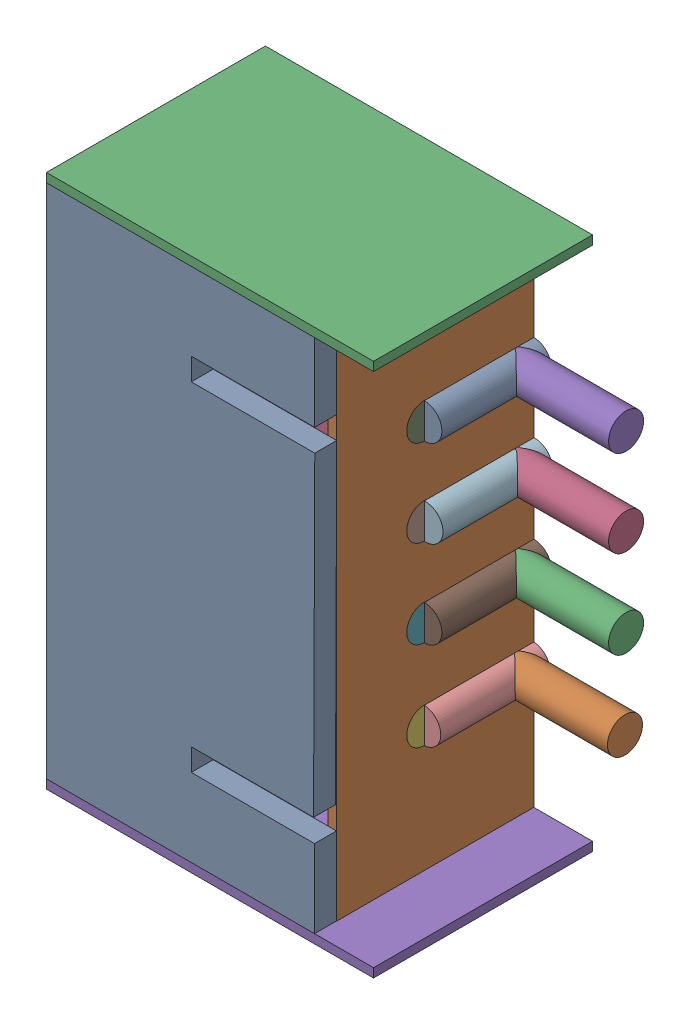
SolidWorks assembly 4PIN, configuration Default. Lengths in mm.
Overall size (8.63 12.19 5).
34 component instances, 7 part files, 0 mates.
Components (placement in the parent):
- 739168144-1: 739168144 [Default] at (53.0673 7.4627 4.5) size (6.13 11.96 0.5)
  - Extruded (28)_1-1: Extruded (28)_1 [Default] at origin size (6.13 11.96 0.5)
- 739168272-1: 739168272 [Default] at (56.0287 7.45 0) size (0.2 12 4.5)
  - Extruded (29)_1-1: Extruded (29)_1 [Default] at origin size (0.2 12 4.5)
- 739168528-1: 739168528 [Default] at (53.738 13.4444 0) size (7.47 0.2 5)
  - Extruded (30)_1-1: Extruded (30)_1 [Default] at origin size (7.47 0.2 5)
- 739168656-1: 739168656 [Default] at (53.066 7.4627 0) size (6.12 11.96 0.5)
  - Extruded (31)_1-1: Extruded (31)_1 [Default] at origin size (6.12 11.96 0.5)
- 739168528_1-1: 739168528_1 [Default] at (53.738 1.4556 0) size (7.47 0.2 5)
  - Extruded (30)_1-1: Extruded (30)_1 [Default] at origin size (7.47 0.2 5)
- 654176208-1: 654176208 [Default] at (56.1305 4.4303 2.5) x (0 0 -1) z (-1 0 0) size (0.8 0.8 5)
  - Cylinder (1)_1-1: Cylinder (1)_1 [Default] at origin size (0.8 0.8 5)
- 654176208_1-1: 654176208_1 [Default] at (56.1305 6.4661 2.5) x (0 0 -1) z (-1 0 0) size (0.8 0.8 5)
  - Cylinder (1)_1-1: Cylinder (1)_1 [Default] at origin size (0.8 0.8 5)
- 654176208_2-1: 654176208_2 [Default] at (56.1305 8.4727 2.5) x (0 0 -1) z (-1 0 0) size (0.8 0.8 5)
  - Cylinder (1)_1-1: Cylinder (1)_1 [Default] at origin size (0.8 0.8 5)
- 654176208_3-1: 654176208_3 [Default] at (56.1305 10.4501 2.5) x (0 0 -1) z (-1 0 0) size (0.8 0.8 5)
  - Cylinder (1)_1-1: Cylinder (1)_1 [Default] at origin size (0.8 0.8 5)
- 654176328-1: 654176328 [Default] at (56.1065 4.4273 0) x (0 1 0) z (0 0 1) size (0.8 0.8 2.5)
  - Cylinder (2)_1-1: Cylinder (2)_1 [Default] at origin size (0.8 0.8 2.5)
- 654176328_1-1: 654176328_1 [Default] at (56.1319 6.4593 0) x (0 1 0) z (0 0 1) size (0.8 0.8 2.5)
  - Cylinder (2)_1-1: Cylinder (2)_1 [Default] at origin size (0.8 0.8 2.5)
- 654176328_2-1: 654176328_2 [Default] at (56.1573 8.4659 0) x (0 1 0) z (0 0 1) size (0.8 0.8 2.5)
  - Cylinder (2)_1-1: Cylinder (2)_1 [Default] at origin size (0.8 0.8 2.5)
- 654176328_3-1: 654176328_3 [Default] at (56.1319 10.4471 0) x (0 1 0) z (0 0 1) size (0.8 0.8 2.5)
  - Cylinder (2)_1-1: Cylinder (2)_1 [Default] at origin size (0.8 0.8 2.5)
- 654176448-1: 654176448 [Default] at (58.6119 4.4302 0.4) x (0 0 -1) z (-1 0 0) size (0.8 0.8 2.5)
  - Cylinder (3)_1-1: Cylinder (3)_1 [Default] at origin size (0.8 0.8 2.5)
- 654176448_1-1: 654176448_1 [Default] at (58.6372 6.4622 0.4) x (0 0 -1) z (-1 0 0) size (0.8 0.8 2.5)
  - Cylinder (3)_1-1: Cylinder (3)_1 [Default] at origin size (0.8 0.8 2.5)
- 654176448_2-1: 654176448_2 [Default] at (58.6372 8.4688 0.4) x (0 0 -1) z (-1 0 0) size (0.8 0.8 2.5)
  - Cylinder (3)_1-1: Cylinder (3)_1 [Default] at origin size (0.8 0.8 2.5)
- 654176448_3-1: 654176448_3 [Default] at (58.6372 10.45 0.4) x (0 0 -1) z (-1 0 0) size (0.8 0.8 2.5)
  - Cylinder (3)_1-1: Cylinder (3)_1 [Default] at origin size (0.8 0.8 2.5)
